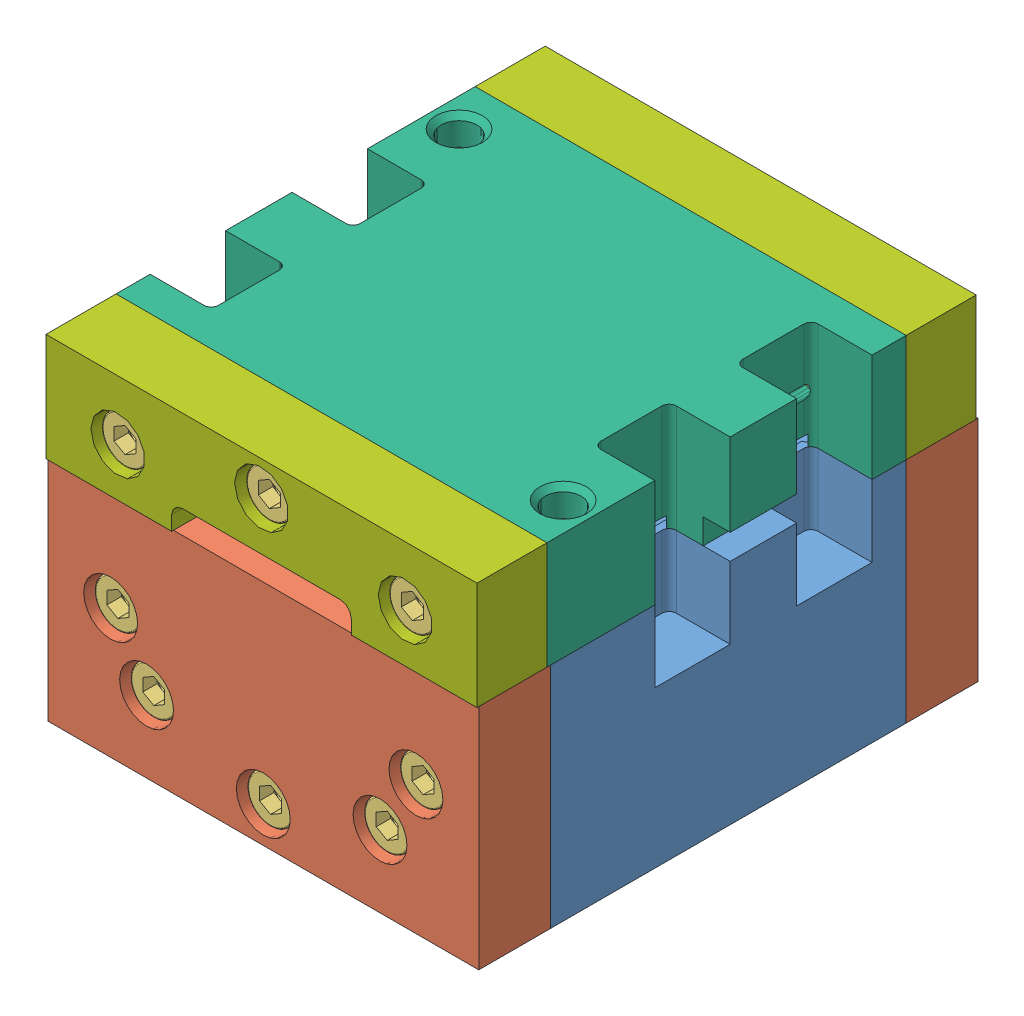
SolidWorks assembly Сборка2, configuration Default. Lengths in mm.
Overall size (120 93.5 139.5).
30 component instances, 7 part files, 3 mates.
Components (placement in the parent):
- Сборка1-1: Сборка1 [По умолчанию] at (46.1455 48.573 101.7886) size (120 88.5 139)
  - Матрица-1: Матрица [Default] at origin size (120 63.5 99)
  - Боковина Пресс-формы.-1: Боковина Пресс-формы. [По умолчанию] at (0 36.1757 49.5) size (120 63.5 20)
  - Боковина Пресс-формы.-3: Боковина Пресс-формы. [По умолчанию] at (0 36.1757 -49.5) x (-1 0 0) z (0 0 -1) size (120 63.5 20)
  - socket head cap screw_iso-1: socket head cap screw_iso [ISO 4762 M8 x 16 - 16N] at (-42.5 36 -67.5) x (0 0 1) z (-1 0 0) size (24 13 13)
  - socket head cap screw_iso-2: socket head cap screw_iso [ISO 4762 M8 x 16 - 16N] at (-32.5 20 -67.5) x (0 0 1) z (-1 0 0) size (24 13 13)
  - socket head cap screw_iso-3: socket head cap screw_iso [ISO 4762 M8 x 16 - 16N] at (0 10 -67.5) x (0 0 1) z (-1 0 0) size (24 13 13)
  - socket head cap screw_iso-4: socket head cap screw_iso [ISO 4762 M8 x 16 - 16N] at (32.5 20 -67.5) x (0 0 1) z (-1 0 0) size (24 13 13)
  - socket head cap screw_iso-5: socket head cap screw_iso [ISO 4762 M8 x 16 - 16N] at (42.5 36 -67.5) x (0 0 1) z (-1 0 0) size (24 13 13)
  - socket head cap screw_iso-6: socket head cap screw_iso [ISO 4762 M8 x 16 - 16N] at (42.5 36 67.5) x (0 0 -1) z (1 0 0) size (24 13 13)
  - socket head cap screw_iso-7: socket head cap screw_iso [ISO 4762 M8 x 16 - 16N] at (32.5 20 67.5) x (0 0 -1) z (1 0 0) size (24 13 13)
  - socket head cap screw_iso-10: socket head cap screw_iso [ISO 4762 M8 x 16 - 16N] at (-42.5 36 67.5) x (0 0 -1) z (1 0 0) size (24 13 13)
  - socket head cap screw_iso-8: socket head cap screw_iso [ISO 4762 M8 x 16 - 16N] at (0 10 67.5) x (0 0 -1) z (1 0 0) size (24 13 13)
  - socket head cap screw_iso-9: socket head cap screw_iso [ISO 4762 M8 x 16 - 16N] at (-32.5 20 67.5) x (0 0 -1) z (1 0 0) size (24 13 13)
  - socket head cap screw_iso-11: socket head cap screw_iso [ISO 4762 M8 x 16 - 16N] at (-32.5 20 67.5) x (0 0 -1) z (1 0 0) size (24 13 13)
  - socket head cap screw_iso-12: socket head cap screw_iso [ISO 4762 M8 x 16 - 16N] at (-42.5 36 67.5) x (0 0 -1) z (1 0 0) size (24 13 13)
  - Направляющая-1: Направляющая [Default] at (52 33.5 38) x (0 1 0) z (-0.458497 0 -0.888696) size (55 10 10)
  - Направляющая-3: Направляющая [Default] at (-51.997 33.5 -37) x (0 1 0) z (-0.61776 0 -0.786366) size (55 10 10)
  - Подставка-2: Подставка [По умолчанию] at (0 48 -27) x (0.955678 0 -0.294415) z (0 -1 0) size (12 12 36)
  - Подставка-3: Подставка [По умолчанию] at (0 48 27) x (0.972927 0 -0.231111) z (0 -1 0) size (12 12 36)
- Сборка3-1: Сборка3 [По умолчанию] at (-38.641 -37.4362 -141.29) size (120 30 139)
  - Пуансон-2: Пуансон [Default] at (84.7865 149.5092 243.5787) size (120 30 100)
  - Боковина пуансона-3: Боковина пуансона [Default] at (84.7865 164.5092 193.5787) x (1 0 0) z (0 0 -1) size (120 30 19.5)
  - Боковина пуансона-4: Боковина пуансона [Default] at (84.7865 164.5092 293.5787) x (-1 0 0) z (0 0 1) size (120 30 19.5)
  - socket head cap screw_iso-1: socket head cap screw_iso [ISO 4762 M8 x 16 - 16N] at (44.7865 163.0092 311.0787) x (0 0 -1) z (1 0 0) size (24 13 13)
  - socket head cap screw_iso-2: socket head cap screw_iso [ISO 4762 M8 x 16 - 16N] at (124.7865 163.0092 311.0787) x (0 0 -1) z (1 0 0) size (24 13 13)
  - socket head cap screw_iso-3: socket head cap screw_iso [ISO 4762 M8 x 16 - 16N] at (85.1489 170.29 311.2498) x (0 0 -1) z (1 0 0) size (24 13 13)
  - socket head cap screw_iso-4: socket head cap screw_iso [ISO 4762 M8 x 16 - 16N] at (124.7865 163.0092 176.0787) x (0 0 1) z (-1 0 0) size (24 13 13)
  - socket head cap screw_iso-5: socket head cap screw_iso [ISO 4762 M8 x 16 - 16N] at (84.7865 170.0092 176.0787) x (0 0 1) z (-1 0 0) size (24 13 13)
  - socket head cap screw_iso-6: socket head cap screw_iso [ISO 4762 M8 x 16 - 16N] at (44.7865 163.0092 176.0787) x (0 0 1) z (-1 0 0) size (24 13 13)
Mates (geometry in assembly coordinates):
- Концентричный25: concentric aligned: cylinder of Сборка3-1/Пуансон-2 through (-5.8515 164.073 64.7886) axis (0 -1 0) radius 5; cylinder of Сборка1-1/Направляющая-3 through (-5.8515 82.073 64.7886) axis (0 -1 0) radius 5
- Концентричный29: concentric anti-aligned: cylinder of Сборка1-1/Матрица-1 through (98.1455 82.073 139.7886) axis (0 1 0) radius 5; cylinder of Сборка3-1/Пуансон-2 through (98.1455 164.073 139.7886) axis (0 -1 0) radius 5
- Совпадение3: coincident anti-aligned: plane of Сборка1-1/Боковина Пресс-формы.-1 through (-13.8545 112.073 171.2886) normal (0 1 0); plane of Сборка3-1/Боковина пуансона-4 through (-13.8545 112.073 171.7886) normal (0 -1 0)
